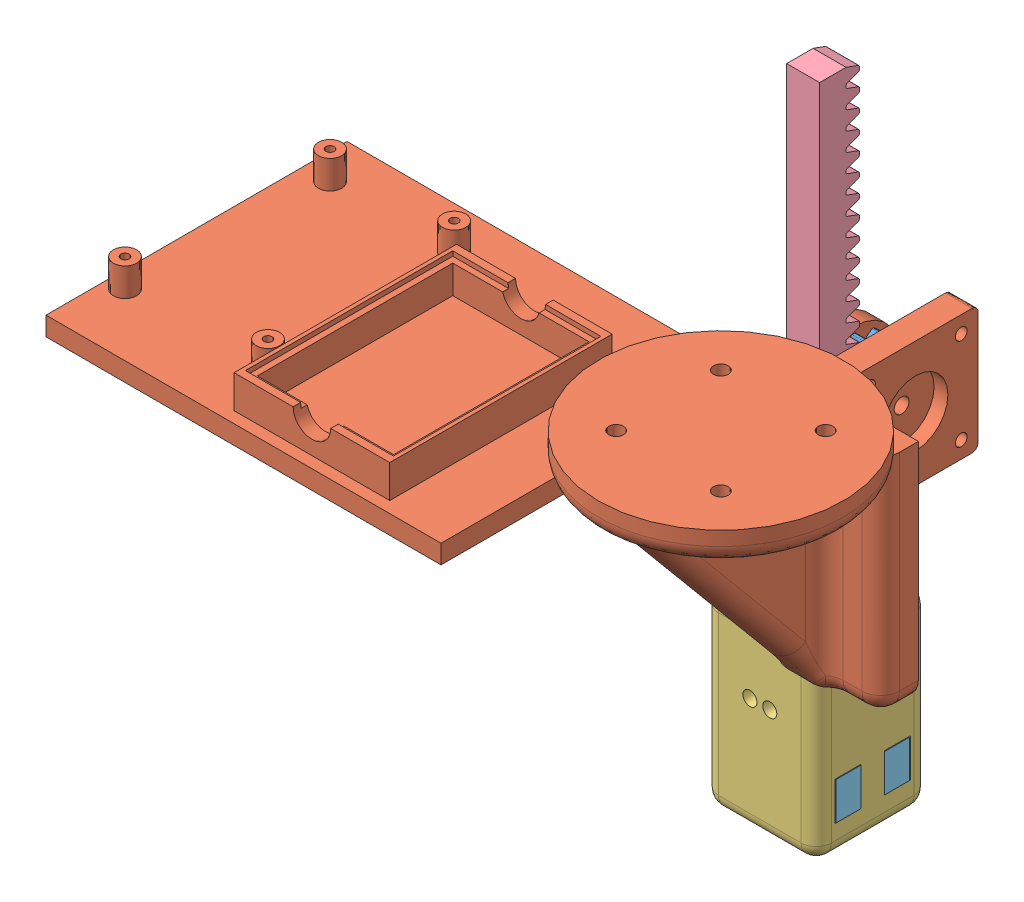
SolidWorks assembly top assembly, configuration Default. Lengths in mm.
Overall size (200.03 215.9 154.35).
6 component instances, 5 part files, 15 mates.
Components (placement in the parent):
- real pinion-1: real pinion [Default] at (31.0443 213.2272 103.6317) x (1 0 0) z (0 -0.968514 -0.248957) size (11.11 26.13 26.09)
- top mount thing-1: top mount thing [Default] at (50.0943 228.4372 167.7693) x (-1 0 0) z (0 0 -1) size (200.03 87.31 154.35)
- cup-1: cup [Default] at (36.6005 100.7635 122.0624) size (38.1 63.5 38.1)
- top plate-2: top plate [Default] at (36.6005 100.7635 122.0366) size (11.11 173.99 13.42)
- locks-1: locks [Default] at (17.5505 117.2735 113.8498) x (0 0 -1) z (1 0 0) size (8.47 12.7 38.1)
- locks-2: locks [Default] at (17.5505 117.2735 130.2751) x (0 0 -1) z (1 0 0) size (8.47 12.7 38.1)
Mates (geometry in assembly coordinates):
- Coincident4: coincident anti-aligned: plane of real pinion-1 through (31.0443 213.2272 103.6317) normal (-1 0 0); plane of top mount thing-1 through (31.0443 213.2272 103.6317) normal (1 0 0)
- Concentric1: concentric aligned: cylinder of real pinion-1 through (42.1568 213.2272 103.6317) axis (-1 0 0) radius 2.7305; cylinder of top mount thing-1 through (31.0443 213.2272 103.6317) axis (-1 0 0) radius 2.51
- Coincident5: coincident anti-aligned: plane of ? through (48.5068 213.2372 107.4062) normal (-1 0 0); plane of top mount thing-1 through (48.5068 213.2372 107.4062) normal (1 0 0)
- Concentric2: concentric aligned: cylinder of ? through (24.3068 213.2372 107.4062) axis (1 0 0) radius 2.5; cylinder of top mount thing-1 through (42.1568 213.2372 107.4062) axis (1 0 0) radius 2.5
- Coincident10: coincident aligned: plane of cup-1 through (36.6005 142.6735 122.0624) normal (0 -1 0); plane of top plate-2 through (36.6005 142.6735 122.0366) normal (0 -1 0)
- Coincident11: coincident anti-aligned: plane of top mount thing-1 through (31.0443 213.2272 103.6317) normal (1 0 0); plane of top plate-2 through (31.0443 100.7635 122.0366) normal (-1 0 0)
- Coincident12: coincident anti-aligned: plane of top mount thing-1 through (75.4943 152.2372 126.4943) normal (0 0 -1); plane of top plate-2 through (42.1568 316.6635 126.4943) normal (0 0 1)
- Coincident13: coincident aligned: plane of cup-1 through (17.5505 164.2635 141.1124) normal (-1 0 0); plane of locks-1 through (17.5505 117.2735 113.8498) normal (-1 0 0)
- Coincident14: coincident anti-aligned: plane of cup-1 through (55.6505 110.9235 109.3624) normal (0 1 0); plane of locks-1 through (55.6505 110.9235 118.0831) normal (0 -1 0)
- Coincident15: coincident anti-aligned: plane of cup-1 through (55.6505 123.8775 118.0831) normal (0 0 -1); plane of locks-1 through (55.6505 110.9235 118.0831) normal (0 0 1)
- Coincident16: coincident aligned: plane of cup-1 through (17.5505 164.2635 141.1124) normal (-1 0 0); plane of locks-2 through (17.5505 117.2735 130.2751) normal (-1 0 0)
- Coincident18: coincident anti-aligned: plane of cup-1 through (55.6505 110.9235 134.7624) normal (0 1 0); plane of locks-2 through (55.6505 110.9235 134.5084) normal (0 -1 0)
- Coincident19: coincident anti-aligned: plane of cup-1 through (55.6505 123.8775 126.0418) normal (0 0 1); plane of locks-2 through (55.6505 110.9235 126.0418) normal (0 0 -1)
- Width1: width anti-aligned: plane of cup-1 through (30.9173 124.8552 126.6471) normal (0 0 -1); plane of cup-1 through (30.9173 124.8552 112.9251) normal (0 0 1); plane of top plate-2 through (42.1568 316.6635 126.4943) normal (0 0 1); plane of top plate-2 through (42.1568 100.7635 113.078) normal (0 0 -1)
- Width2: width anti-aligned: plane of cup-1 through (42.2838 124.8552 112.9251) normal (-1 0 0); plane of cup-1 through (30.9173 124.8552 112.9251) normal (1 0 0); plane of top plate-2 through (42.1568 100.7635 122.0366) normal (1 0 0); plane of top plate-2 through (31.0443 100.7635 122.0366) normal (-1 0 0)
